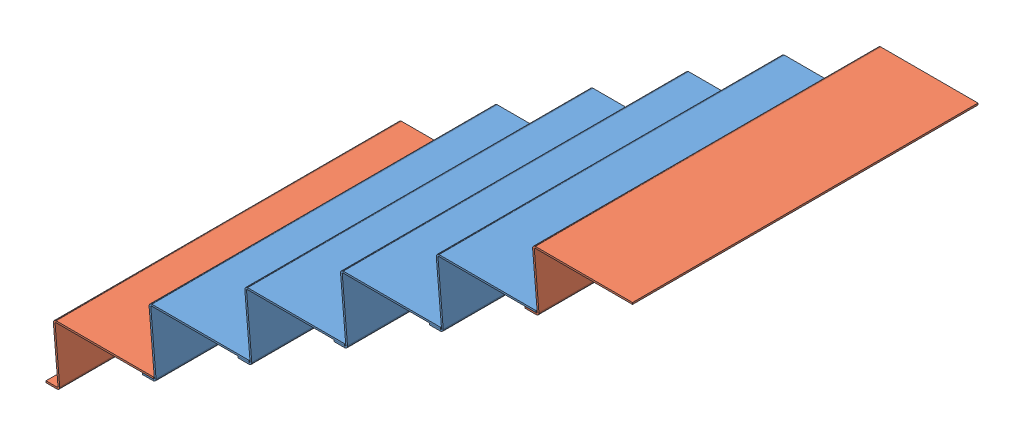
SolidWorks assembly sestava schody, configuration Default. Lengths in mm.
Overall size (1862.15 1096.89 1000).
6 component instances, 2 part files, 8 mates.
Components (placement in the parent):
- schod str200 -- 14-6-2018-1: schod str200 -- 14-6-2018 [Default] at (541.1177 678.6606 1217.4985) size (308.81 190 1000)
- schod str200 -- 14-6-2018-2: schod str200 -- 14-6-2018 [Default] at (818.2062 858.6606 1217.4985) size (308.81 190 1000)
- schod str200 -- 14-6-2018-3: schod str200 -- 14-6-2018 [Default] at (1095.2947 1038.6606 1217.4985) size (308.81 190 1000)
- schod str200 -- 14-6-2018-4: schod str200 -- 14-6-2018 [Default] at (1372.3833 1218.6606 1217.4985) size (308.81 190 1000)
- schod00 str200 -- 14-6-2018-1: schod00 str200 -- 14-6-2018 [Default] at (264.0292 498.6606 1217.4985) size (310.56 170 1000)
- schod00 str200 -- 14-6-2018-2: schod00 str200 -- 14-6-2018 [Default] at (1651.2216 1378.6606 1217.4985) size (310.56 170 1000)
Mates (geometry in assembly coordinates):
- Sjednocená1: coincident anti-aligned: plane of schod str200 -- 14-6-2018-1 through (541.1177 673.6606 217.4985) normal (0 -1 0); plane of schod str200 -- 14-6-2018-2 through (544.3916 673.6606 217.4985) normal (0 1 0)
- Sjednocená2: coincident: point of schod str200 -- 14-6-2018-1; point of schod str200 -- 14-6-2018-2
- Sjednocená3: coincident: point of schod str200 -- 14-6-2018-2; point of schod str200 -- 14-6-2018-3
- Sjednocená4: coincident: point of schod str200 -- 14-6-2018-3; point of schod str200 -- 14-6-2018-4
- Sjednocená5: coincident: point of schod str200 -- 14-6-2018-4; point of ?
- Sjednocená6: coincident: point of ?; point of ?
- Sjednocená7: coincident: point of schod str200 -- 14-6-2018-1; point of schod00 str200 -- 14-6-2018-1
- Sjednocená8: coincident: point of schod str200 -- 14-6-2018-4; point of schod00 str200 -- 14-6-2018-2
